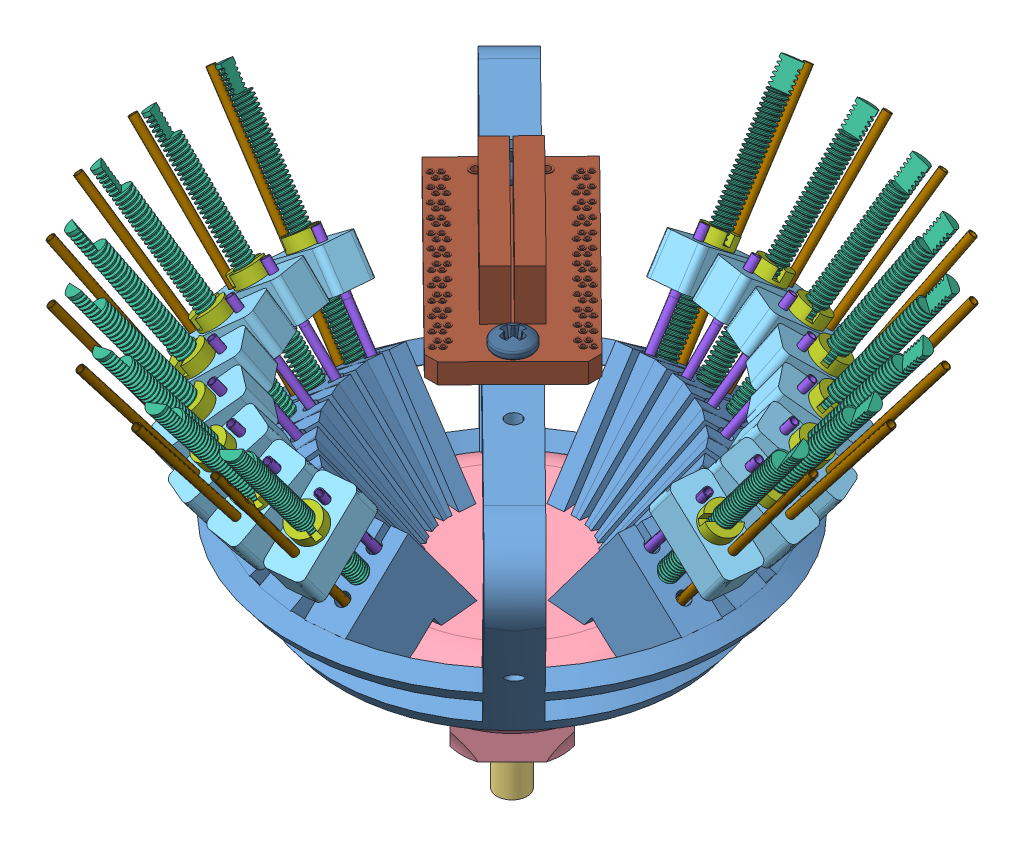
SolidWorks assembly DriveAssembly, configuration Default. Lengths in mm.
Overall size (54.83 40.66 54.81).
118 component instances, 11 part files, 91 mates.
Components (placement in the parent):
- drive_circle_16-1: drive_circle_16 [Default] at (0.3829 7.146 2.514) x (0.996757 0 0.080473) z (-0.080473 0 0.996757) size (45.82 35.06 38.44)
- 30g Tubing Curved-1: 30g Tubing Curved [Default] at (-0.6864 5.748 2.4277) x (0.996757 0 0.080473) z (-0.080473 0 0.996757) size (12.56 22.36 0.32)
- 30g Tubing Curved-5: 30g Tubing Curved [Default] at (-0.484 6 2.6618) x (0.985792 0 -0.167972) z (0.167972 0 0.985792) size (12.56 22.36 0.32)
- 30g Tubing Curved-13: 30g Tubing Curved [Default] at (-0.4207 6 2.8711) x (0.91386 0 -0.406029) z (0.406029 0 0.91386) size (12.56 22.36 0.32)
- 30g Tubing Curved-14: 30g Tubing Curved [Default] at (-0.3078 6 3.0583) x (0.78541 0 -0.618976) z (0.618976 0 0.78541) size (12.56 22.36 0.32)
- 30g Tubing Curved-15: 30g Tubing Curved [Default] at (-0.1521 6 3.2119) x (0.608386 0 -0.793641) z (0.793641 0 0.608386) size (12.56 22.36 0.32)
- 30g Tubing Curved-16: 30g Tubing Curved [Default] at (0.0366 6 3.3224) x (0.393737 0 -0.919223) z (0.919223 0 0.393737) size (12.56 22.36 0.32)
- 30g Tubing Curved-17: 30g Tubing Curved [Default] at (0.2468 6 3.3828) x (0.154736 0 -0.987956) z (0.987956 0 0.154736) size (12.56 22.36 0.32)
- 30g Tubing Curved-18: 30g Tubing Curved [Default] at (0.4654 6 3.3895) x (-0.093834 0 -0.995588) z (0.995588 0 -0.093834) size (12.56 22.36 0.32)
- 30g Tubing Curved-27: 30g Tubing Curved [Default] at (1.2594 6 2.5848) x (-0.996757 0 -0.080473) z (0.080473 0 -0.996757) size (12.56 22.36 0.32)
- 30g Tubing Curved-28: 30g Tubing Curved [Default] at (1.2497 6 2.3663) x (-0.985792 0 0.167972) z (-0.167972 0 -0.985792) size (12.56 22.36 0.32)
- 30g Tubing Curved-29: 30g Tubing Curved [Default] at (1.1865 6 2.157) x (-0.91386 0 0.406029) z (-0.406029 0 -0.91386) size (12.56 22.36 0.32)
- 30g Tubing Curved-30: 30g Tubing Curved [Default] at (1.0735 6 1.9697) x (-0.78541 0 0.618976) z (-0.618976 0 -0.78541) size (12.56 22.36 0.32)
- 30g Tubing Curved-31: 30g Tubing Curved [Default] at (0.9179 6 1.8161) x (-0.608386 0 0.793641) z (-0.793641 0 -0.608386) size (12.56 22.36 0.32)
- 30g Tubing Curved-34: 30g Tubing Curved [Default] at (0.7291 6 1.7057) x (-0.393737 0 0.919223) z (-0.919223 0 -0.393737) size (12.56 22.36 0.32)
- 30g Tubing Curved-35: 30g Tubing Curved [Default] at (0.5189 6 1.6453) x (-0.154736 0 0.987956) z (-0.987956 0 -0.154736) size (12.56 22.36 0.32)
- 30g Tubing Curved-36: 30g Tubing Curved [Default] at (0.3004 6 1.6386) x (0.093834 0 0.995588) z (-0.995588 0 0.093834) size (12.56 22.36 0.32)
- MainCanula-1: MainCanula [Default] at (0.3829 1.748 2.514) x (-0.437751 0 0.899096) z (-0.899096 0 -0.437751) size (2.41 8 2.41)
- AcrylicFill-1: AcrylicFill [Default] at (0.3829 3.9937 2.514) x (0.711094 0 0.703097) z (-0.703097 0 0.711094) size (25 12 25)
- Shuttle Assembly-18: Shuttle Assembly [Default] at (16.7091 21.9961 9.3723) x (-0.79078 0.608761 -0.063844) z (0.080473 0 -0.996757) size (6.5 25.22 3.31)
  - Shuttle-1: Shuttle [Default] at (2.5582 1.9761 5.5221) size (6.5 3 3)
  - Threaded Rod 25mm-1: Threaded Rod 25mm [Default] at (2.5582 -8.5786 5.5221) x (0.813094 0 0.582132) z (-0.582132 0 0.813094) size (1.64 25.22 1.64)
  - Grooved Nut-1: Grooved Nut [Default] at (2.5582 1.9761 5.5221) x (0.414361 0 -0.910113) z (0.910113 0 0.414361) size (2.5 4 2.5)
  - 23g Tubing 13mm-1: 23g Tubing 13mm [Default] at (4.3082 -7.0239 5.5221) size (0.64 13 0.64)
  - 23g Tubing 25mm-1: 23g Tubing 25mm [Default] at (0.8082 -8.5786 5.5221) size (0.62 25 0.62)
- Shuttle Assembly-19: Shuttle Assembly [Default] at (17.8965 21.9961 5.1316) x (-0.782081 0.608761 0.133261) z (-0.167972 0 -0.985792) size (6.5 25.22 3.31)
  - Shuttle-1: Shuttle [Default] at (2.5582 1.9761 5.5221) size (6.5 3 3)
  - Threaded Rod 25mm-1: Threaded Rod 25mm [Default] at (2.5582 -8.5786 5.5221) x (0.813094 0 0.582132) z (-0.582132 0 0.813094) size (1.64 25.22 1.64)
  - Grooved Nut-1: Grooved Nut [Default] at (2.5582 1.9761 5.5221) x (0.414361 0 -0.910113) z (0.910113 0 0.414361) size (2.5 4 2.5)
  - 23g Tubing 13mm-1: 23g Tubing 13mm [Default] at (4.3082 -7.0239 5.5221) size (0.64 13 0.64)
  - 23g Tubing 25mm-1: 23g Tubing 25mm [Default] at (0.8082 -8.5786 5.5221) size (0.62 25 0.62)
- Shuttle Assembly-20: Shuttle Assembly [Default] at (18.0009 21.9961 0.729) x (-0.725014 0.608761 0.322125) z (-0.406029 0 -0.91386) size (6.5 25.22 3.31)
  - Shuttle-1: Shuttle [Default] at (2.5582 1.9761 5.5221) size (6.5 3 3)
  - Threaded Rod 25mm-1: Threaded Rod 25mm [Default] at (2.5582 -8.5786 5.5221) x (0.813094 0 0.582132) z (-0.582132 0 0.813094) size (1.64 25.22 1.64)
  - Grooved Nut-1: Grooved Nut [Default] at (2.5582 1.9761 5.5221) x (0.414361 0 -0.910113) z (0.910113 0 0.414361) size (2.5 4 2.5)
  - 23g Tubing 13mm-1: 23g Tubing 13mm [Default] at (4.3082 -7.0239 5.5221) size (0.64 13 0.64)
  - 23g Tubing 25mm-1: 23g Tubing 25mm [Default] at (0.8082 -8.5786 5.5221) size (0.62 25 0.62)
- Shuttle Assembly-21: Shuttle Assembly [Default] at (17.0156 21.9961 -3.5632) x (-0.623108 0.608761 0.491066) z (-0.618976 0 -0.78541) size (6.5 25.22 3.31)
  - Shuttle-1: Shuttle [Default] at (2.5582 1.9761 5.5221) size (6.5 3 3)
  - Threaded Rod 25mm-1: Threaded Rod 25mm [Default] at (2.5582 -8.5786 5.5221) x (0.813094 0 0.582132) z (-0.582132 0 0.813094) size (1.64 25.22 1.64)
  - Grooved Nut-1: Grooved Nut [Default] at (2.5582 1.9761 5.5221) x (0.414361 0 -0.910113) z (0.910113 0 0.414361) size (2.5 4 2.5)
  - 23g Tubing 13mm-1: 23g Tubing 13mm [Default] at (4.3082 -7.0239 5.5221) size (0.64 13 0.64)
  - 23g Tubing 25mm-1: 23g Tubing 25mm [Default] at (0.8082 -8.5786 5.5221) size (0.62 25 0.62)
- Shuttle Assembly-22: Shuttle Assembly [Default] at (15.0017 21.9961 -7.4795) x (-0.482665 0.608761 0.629638) z (-0.793641 0 -0.608386) size (6.5 25.22 3.31)
  - Shuttle-1: Shuttle [Default] at (2.5582 1.9761 5.5221) size (6.5 3 3)
  - Threaded Rod 25mm-1: Threaded Rod 25mm [Default] at (2.5582 -8.5786 5.5221) x (0.813094 0 0.582132) z (-0.582132 0 0.813094) size (1.64 25.22 1.64)
  - Grooved Nut-1: Grooved Nut [Default] at (2.5582 1.9761 5.5221) x (0.414361 0 -0.910113) z (0.910113 0 0.414361) size (2.5 4 2.5)
  - 23g Tubing 13mm-1: 23g Tubing 13mm [Default] at (4.3082 -7.0239 5.5221) size (0.64 13 0.64)
  - 23g Tubing 25mm-1: 23g Tubing 25mm [Default] at (0.8082 -8.5786 5.5221) size (0.62 25 0.62)
- Shuttle Assembly-23: Shuttle Assembly [Default] at (12.0836 21.9961 -10.7778) x (-0.312372 0.608761 0.729269) z (-0.919223 0 -0.393737) size (6.5 25.22 3.31)
  - Shuttle-1: Shuttle [Default] at (2.5582 1.9761 5.5221) size (6.5 3 3)
  - Threaded Rod 25mm-1: Threaded Rod 25mm [Default] at (2.5582 -8.5786 5.5221) x (0.813094 0 0.582132) z (-0.582132 0 0.813094) size (1.64 25.22 1.64)
  - Grooved Nut-1: Grooved Nut [Default] at (2.5582 1.9761 5.5221) x (0.414361 0 -0.910113) z (0.910113 0 0.414361) size (2.5 4 2.5)
  - 23g Tubing 13mm-1: 23g Tubing 13mm [Default] at (4.3082 -7.0239 5.5221) size (0.64 13 0.64)
  - 23g Tubing 25mm-1: 23g Tubing 25mm [Default] at (0.8082 -8.5786 5.5221) size (0.62 25 0.62)
- Shuttle Assembly-24: Shuttle Assembly [Default] at (8.442 21.9961 -13.254) x (-0.12276 0.608761 0.783798) z (-0.987956 0 -0.154736) size (6.5 25.22 3.31)
  - Shuttle-1: Shuttle [Default] at (2.5582 1.9761 5.5221) size (6.5 3 3)
  - Threaded Rod 25mm-1: Threaded Rod 25mm [Default] at (2.5582 -8.5786 5.5221) x (0.813094 0 0.582132) z (-0.582132 0 0.813094) size (1.64 25.22 1.64)
  - Grooved Nut-1: Grooved Nut [Default] at (2.5582 1.9761 5.5221) x (0.414361 0 -0.910113) z (0.910113 0 0.414361) size (2.5 4 2.5)
  - 23g Tubing 13mm-1: 23g Tubing 13mm [Default] at (4.3082 -7.0239 5.5221) size (0.64 13 0.64)
  - 23g Tubing 25mm-1: 23g Tubing 25mm [Default] at (0.8082 -8.5786 5.5221) size (0.62 25 0.62)
- Shuttle Assembly-25: Shuttle Assembly [Default] at (4.3019 21.9961 -14.755) x (0.074444 0.608761 0.789853) z (-0.995588 0 0.093834) size (6.5 25.22 3.31)
  - Shuttle-1: Shuttle [Default] at (2.5582 1.9761 5.5221) size (6.5 3 3)
  - Threaded Rod 25mm-1: Threaded Rod 25mm [Default] at (2.5582 -8.5786 5.5221) x (0.813094 0 0.582132) z (-0.582132 0 0.813094) size (1.64 25.22 1.64)
  - Grooved Nut-1: Grooved Nut [Default] at (2.5582 1.9761 5.5221) x (0.414361 0 -0.910113) z (0.910113 0 0.414361) size (2.5 4 2.5)
  - 23g Tubing 13mm-1: 23g Tubing 13mm [Default] at (4.3082 -7.0239 5.5221) size (0.64 13 0.64)
  - 23g Tubing 25mm-1: 23g Tubing 25mm [Default] at (0.8082 -8.5786 5.5221) size (0.62 25 0.62)
- Shuttle Assembly-26: Shuttle Assembly [Default] at (-15.9433 21.9961 -4.3442) x (0.79078 0.608761 0.063844) z (-0.080473 0 0.996757) size (6.5 25.22 3.31)
  - Shuttle-1: Shuttle [Default] at (2.5582 1.9761 5.5221) size (6.5 3 3)
  - Threaded Rod 25mm-1: Threaded Rod 25mm [Default] at (2.5582 -8.5786 5.5221) x (0.813094 0 0.582132) z (-0.582132 0 0.813094) size (1.64 25.22 1.64)
  - Grooved Nut-1: Grooved Nut [Default] at (2.5582 1.9761 5.5221) x (0.414361 0 -0.910113) z (0.910113 0 0.414361) size (2.5 4 2.5)
  - 23g Tubing 13mm-1: 23g Tubing 13mm [Default] at (4.3082 -7.0239 5.5221) size (0.64 13 0.64)
  - 23g Tubing 25mm-1: 23g Tubing 25mm [Default] at (0.8082 -8.5786 5.5221) size (0.62 25 0.62)
- Shuttle Assembly-27: Shuttle Assembly [Default] at (-17.1308 21.9961 -0.1035) x (0.782081 0.608761 -0.133261) z (0.167972 0 0.985792) size (6.5 25.22 3.31)
  - Shuttle-1: Shuttle [Default] at (2.5582 1.9761 5.5221) size (6.5 3 3)
  - Threaded Rod 25mm-1: Threaded Rod 25mm [Default] at (2.5582 -8.5786 5.5221) x (0.813094 0 0.582132) z (-0.582132 0 0.813094) size (1.64 25.22 1.64)
  - Grooved Nut-1: Grooved Nut [Default] at (2.5582 1.9761 5.5221) x (0.414361 0 -0.910113) z (0.910113 0 0.414361) size (2.5 4 2.5)
  - 23g Tubing 13mm-1: 23g Tubing 13mm [Default] at (4.3082 -7.0239 5.5221) size (0.64 13 0.64)
  - 23g Tubing 25mm-1: 23g Tubing 25mm [Default] at (0.8082 -8.5786 5.5221) size (0.62 25 0.62)
- Shuttle Assembly-28: Shuttle Assembly [Default] at (-17.2351 21.9961 4.2991) x (0.725014 0.608761 -0.322125) z (0.406029 0 0.91386) size (6.5 25.22 3.31)
  - Shuttle-1: Shuttle [Default] at (2.5582 1.9761 5.5221) size (6.5 3 3)
  - Threaded Rod 25mm-1: Threaded Rod 25mm [Default] at (2.5582 -8.5786 5.5221) x (0.813094 0 0.582132) z (-0.582132 0 0.813094) size (1.64 25.22 1.64)
  - Grooved Nut-1: Grooved Nut [Default] at (2.5582 1.9761 5.5221) x (0.414361 0 -0.910113) z (0.910113 0 0.414361) size (2.5 4 2.5)
  - 23g Tubing 13mm-1: 23g Tubing 13mm [Default] at (4.3082 -7.0239 5.5221) size (0.64 13 0.64)
  - 23g Tubing 25mm-1: 23g Tubing 25mm [Default] at (0.8082 -8.5786 5.5221) size (0.62 25 0.62)
- Shuttle Assembly-29: Shuttle Assembly [Default] at (-16.2499 21.9961 8.5913) x (0.623108 0.608761 -0.491066) z (0.618976 0 0.78541) size (6.5 25.22 3.31)
  - Shuttle-1: Shuttle [Default] at (2.5582 1.9761 5.5221) size (6.5 3 3)
  - Threaded Rod 25mm-1: Threaded Rod 25mm [Default] at (2.5582 -8.5786 5.5221) x (0.813094 0 0.582132) z (-0.582132 0 0.813094) size (1.64 25.22 1.64)
  - Grooved Nut-1: Grooved Nut [Default] at (2.5582 1.9761 5.5221) x (0.414361 0 -0.910113) z (0.910113 0 0.414361) size (2.5 4 2.5)
  - 23g Tubing 13mm-1: 23g Tubing 13mm [Default] at (4.3082 -7.0239 5.5221) size (0.64 13 0.64)
  - 23g Tubing 25mm-1: 23g Tubing 25mm [Default] at (0.8082 -8.5786 5.5221) size (0.62 25 0.62)
- Shuttle Assembly-30: Shuttle Assembly [Default] at (-14.2359 21.9961 12.5076) x (0.482665 0.608761 -0.629638) z (0.793641 0 0.608386) size (6.5 25.22 3.31)
  - Shuttle-1: Shuttle [Default] at (2.5582 1.9761 5.5221) size (6.5 3 3)
  - Threaded Rod 25mm-1: Threaded Rod 25mm [Default] at (2.5582 -8.5786 5.5221) x (0.813094 0 0.582132) z (-0.582132 0 0.813094) size (1.64 25.22 1.64)
  - Grooved Nut-1: Grooved Nut [Default] at (2.5582 1.9761 5.5221) x (0.414361 0 -0.910113) z (0.910113 0 0.414361) size (2.5 4 2.5)
  - 23g Tubing 13mm-1: 23g Tubing 13mm [Default] at (4.3082 -7.0239 5.5221) size (0.64 13 0.64)
  - 23g Tubing 25mm-1: 23g Tubing 25mm [Default] at (0.8082 -8.5786 5.5221) size (0.62 25 0.62)
- Shuttle Assembly-32: Shuttle Assembly [Default] at (-11.3179 21.9961 15.8059) x (0.312372 0.608761 -0.729269) z (0.919223 0 0.393737) size (6.5 25.22 3.31)
  - Shuttle-1: Shuttle [Default] at (2.5582 1.9761 5.5221) size (6.5 3 3)
  - Threaded Rod 25mm-1: Threaded Rod 25mm [Default] at (2.5582 -8.5786 5.5221) x (0.813094 0 0.582132) z (-0.582132 0 0.813094) size (1.64 25.22 1.64)
  - Grooved Nut-1: Grooved Nut [Default] at (2.5582 1.9761 5.5221) x (0.414361 0 -0.910113) z (0.910113 0 0.414361) size (2.5 4 2.5)
  - 23g Tubing 13mm-1: 23g Tubing 13mm [Default] at (4.3082 -7.0239 5.5221) size (0.64 13 0.64)
  - 23g Tubing 25mm-1: 23g Tubing 25mm [Default] at (0.8082 -8.5786 5.5221) size (0.62 25 0.62)
- Shuttle Assembly-33: Shuttle Assembly [Default] at (-7.6762 21.9961 18.2821) x (0.12276 0.608761 -0.783798) z (0.987956 0 0.154736) size (6.5 25.22 3.31)
  - Shuttle-1: Shuttle [Default] at (2.5582 1.9761 5.5221) size (6.5 3 3)
  - Threaded Rod 25mm-1: Threaded Rod 25mm [Default] at (2.5582 -8.5786 5.5221) x (0.813094 0 0.582132) z (-0.582132 0 0.813094) size (1.64 25.22 1.64)
  - Grooved Nut-1: Grooved Nut [Default] at (2.5582 1.9761 5.5221) x (0.414361 0 -0.910113) z (0.910113 0 0.414361) size (2.5 4 2.5)
  - 23g Tubing 13mm-1: 23g Tubing 13mm [Default] at (4.3082 -7.0239 5.5221) size (0.64 13 0.64)
  - 23g Tubing 25mm-1: 23g Tubing 25mm [Default] at (0.8082 -8.5786 5.5221) size (0.62 25 0.62)
- Shuttle Assembly-34: Shuttle Assembly [Default] at (-3.5361 21.9961 19.7831) x (-0.074444 0.608761 -0.789853) z (0.995588 0 -0.093834) size (6.5 25.22 3.31)
  - Shuttle-1: Shuttle [Default] at (2.5582 1.9761 5.5221) size (6.5 3 3)
  - Threaded Rod 25mm-1: Threaded Rod 25mm [Default] at (2.5582 -8.5786 5.5221) x (0.813094 0 0.582132) z (-0.582132 0 0.813094) size (1.64 25.22 1.64)
  - Grooved Nut-1: Grooved Nut [Default] at (2.5582 1.9761 5.5221) x (0.414361 0 -0.910113) z (0.910113 0 0.414361) size (2.5 4 2.5)
  - 23g Tubing 13mm-1: 23g Tubing 13mm [Default] at (4.3082 -7.0239 5.5221) size (0.64 13 0.64)
  - 23g Tubing 25mm-1: 23g Tubing 25mm [Default] at (0.8082 -8.5786 5.5221) size (0.62 25 0.62)
- McMasterCarr_0-80_91772A052-1: McMasterCarr_0-80_91772A052 [91772A052] at (-5.6677 33.0313 -3.4559) x (1 0 0) z (0 1 0) size (2.95 2.95 6.38)
- McMasterCarr_0-80_91772A052-2: McMasterCarr_0-80_91772A052 [91772A052] at (6.4334 33.0313 8.484) x (1 0 0) z (0 1 0) size (2.95 2.95 6.38)
- EIB_64_Omnetics-1: EIB_64_Omnetics [Default] at (0.3829 34.6188 2.514) x (0.711833 0 0.702349) z (-0.702349 0 0.711833) size (20 5.6 10)
Mates (geometry in assembly coordinates):
- Concentric1: concentric aligned: circle of drive_circle_16-1; circle of 30g Tubing Curved-1
- Concentric5: concentric aligned: circle of 30g Tubing Curved-5; circle of drive_circle_16-1
- Concentric6: concentric aligned: circle of 30g Tubing Curved-13; circle of drive_circle_16-1
- Concentric7: concentric aligned: circle of 30g Tubing Curved-14; circle of drive_circle_16-1
- Concentric8: concentric aligned: circle of 30g Tubing Curved-15; circle of drive_circle_16-1
- Concentric9: concentric aligned: circle of 30g Tubing Curved-16; circle of drive_circle_16-1
- Concentric10: concentric aligned: circle of 30g Tubing Curved-17; circle of drive_circle_16-1
- Concentric11: concentric aligned: circle of 30g Tubing Curved-18; circle of drive_circle_16-1
- Parallel1: parallel anti-aligned: plane of 30g Tubing Curved-5 through (-0.2868 0 2.6282) normal (0 -1 0); plane of assembly through (0 0 0) normal (0 1 0)
- Parallel2: parallel anti-aligned: plane of 30g Tubing Curved-1 through (-0.4871 -0.252 2.4438) normal (0 -1 0); plane of assembly through (0 0 0) normal (0 1 0)
- Parallel3: parallel anti-aligned: plane of 30g Tubing Curved-18 through (0.4466 0 3.1904) normal (0 -1 0); plane of assembly through (0 0 0) normal (0 1 0)
- Parallel4: parallel anti-aligned: plane of 30g Tubing Curved-17 through (0.2777 0 3.1852) normal (0 -1 0); plane of assembly through (0 0 0) normal (0 1 0)
- Parallel5: parallel anti-aligned: plane of 30g Tubing Curved-16 through (0.1154 0 3.1385) normal (0 -1 0); plane of assembly through (0 0 0) normal (0 1 0)
- Parallel6: parallel anti-aligned: plane of 30g Tubing Curved-15 through (-0.0304 0 3.0532) normal (0 -1 0); plane of assembly through (0 0 0) normal (0 1 0)
- Parallel7: parallel anti-aligned: plane of 30g Tubing Curved-14 through (-0.1507 0 2.9346) normal (0 -1 0); plane of assembly through (0 0 0) normal (0 1 0)
- Parallel8: parallel anti-aligned: plane of 30g Tubing Curved-13 through (-0.238 0 2.7899) normal (0 -1 0); plane of assembly through (0 0 0) normal (0 1 0)
- Distance9: distance = 0 mm aligned: plane of 30g Tubing Curved-1 through (-0.4871 -0.252 2.4438) normal (0 -1 0); plane of MainCanula-1 through (0.3829 -0.252 2.514) normal (0 -1 0)
- Concentric12: concentric aligned: line of drive_circle_16-1 through (0.3829 7.146 2.514) axis (0 1 0); circle of MainCanula-1
- Parallel11: parallel anti-aligned: plane of MainCanula-1 through (0.3829 7.748 2.514) normal (0 1 0); plane of AcrylicFill-1 through (0.3829 3.9937 2.514) normal (0 -1 0)
- Concentric13: concentric aligned: circle of AcrylicFill-1; circle of MainCanula-1
- StabilizerAndDriveConcentric: concentric aligned: circle of drive_circle_16-1; circle of Shuttle Assembly-18/23g Tubing 25mm-1
- BrassNutAndDriveConcentric: concentric anti-aligned: circle of drive_circle_16-1; circle of Shuttle Assembly-18/Grooved Nut-1
- ShuttleHeight: distance = 7 mm aligned: plane of Shuttle Assembly-18/Shuttle-1 through (18.15 27.5012 3.9485) normal (0.606787 0.793353 0.048989); plane of drive_circle_16-1 through (11.4531 23.9262 1.9029) normal (0.606787 0.793353 0.048989)
- Concentric36: concentric aligned: circle of Shuttle Assembly-19/23g Tubing 25mm-1; circle of drive_circle_16-1
- Concentric37: concentric anti-aligned: unknown of Shuttle Assembly-19/Grooved Nut-1; unknown of drive_circle_16-1
- Distance11: distance = 7 mm aligned: plane of Shuttle Assembly-19/Shuttle-1 through (17.9545 27.5012 -0.48) normal (0.600112 0.793353 -0.102255); plane of drive_circle_16-1 through (10.96 23.9262 -0.8098) normal (0.600112 0.793353 -0.102255)
- Concentric38: concentric aligned: circle of Shuttle Assembly-20/23g Tubing 25mm-1; circle of drive_circle_16-1
- Concentric39: concentric anti-aligned: unknown of Shuttle Assembly-20/Grooved Nut-1; unknown of drive_circle_16-1
- Distance12: distance = 7 mm aligned: plane of Shuttle Assembly-20/Shuttle-1 through (16.6724 27.5012 -4.7234) normal (0.556323 0.793353 -0.247175); plane of drive_circle_16-1 through (9.8128 23.9262 -3.3171) normal (0.556323 0.793353 -0.247175)
- Concentric40: concentric aligned: circle of drive_circle_16-1; circle of Shuttle Assembly-21/23g Tubing 25mm-1
- Concentric41: concentric anti-aligned: unknown of drive_circle_16-1; unknown of Shuttle Assembly-21/Grooved Nut-1
- Distance13: distance = 7 mm aligned: plane of Shuttle Assembly-21/Shuttle-1 through (14.3827 27.5012 -8.5191) normal (0.478127 0.793353 -0.376808); plane of drive_circle_16-1 through (8.0823 23.9262 -5.4636) normal (0.478127 0.793353 -0.376808)
- Concentric42: concentric aligned: circle of drive_circle_16-1; circle of Shuttle Assembly-22/23g Tubing 25mm-1
- Concentric43: concentric anti-aligned: unknown of drive_circle_16-1; unknown of Shuttle Assembly-22/Grooved Nut-1
- Distance14: distance = 7 mm aligned: plane of Shuttle Assembly-22/Shuttle-1 through (11.2273 27.5012 -11.6325) normal (0.370362 0.793353 -0.483138); plane of drive_circle_16-1 through (5.8757 23.9262 -7.1168) normal (0.370362 0.793353 -0.483138)
- Concentric44: concentric aligned: circle of drive_circle_16-1; circle of Shuttle Assembly-23/23g Tubing 25mm-1
- Concentric45: concentric anti-aligned: unknown of drive_circle_16-1; unknown of Shuttle Assembly-23/Grooved Nut-1
- Distance15: distance = 7 mm aligned: plane of Shuttle Assembly-23/Shuttle-1 through (7.4012 27.5012 -13.871) normal (0.239692 0.793353 -0.559588); plane of drive_circle_16-1 through (3.3293 23.9262 -8.1744) normal (0.239692 0.793353 -0.559588)
- Concentric46: concentric aligned: circle of drive_circle_16-1; circle of Shuttle Assembly-24/23g Tubing 25mm-1
- Concentric47: concentric anti-aligned: unknown of drive_circle_16-1; unknown of Shuttle Assembly-24/Grooved Nut-1
- Distance16: distance = 7 mm aligned: plane of Shuttle Assembly-24/Shuttle-1 through (3.141 27.5012 -15.0962) normal (0.094197 0.793353 -0.601429); plane of drive_circle_16-1 through (0.6007 23.9262 -8.571) normal (0.094197 0.793353 -0.601429)
- Concentric48: concentric aligned: circle of drive_circle_16-1; circle of Shuttle Assembly-25/23g Tubing 25mm-1
- Concentric49: concentric anti-aligned: unknown of drive_circle_16-1; unknown of Shuttle Assembly-25/Grooved Nut-1
- Distance17: distance = 7 mm aligned: plane of Shuttle Assembly-25/Shuttle-1 through (-1.2897 27.5012 -15.2322) normal (-0.057123 0.793353 -0.606075); plane of drive_circle_16-1 through (-2.1413 23.9262 -8.2819) normal (-0.057123 0.793353 -0.606075)
- Concentric50: concentric anti-aligned: circle of drive_circle_16-1; circle of Shuttle Assembly-26/23g Tubing 25mm-1
- Concentric51: concentric aligned: unknown of drive_circle_16-1; unknown of Shuttle Assembly-26/Grooved Nut-1
- Distance18: distance = 7 mm aligned: plane of Shuttle Assembly-26/Shuttle-1 through (-17.3842 27.5012 1.0796) normal (-0.606787 0.793353 -0.048989); plane of drive_circle_16-1 through (-10.446 23.9262 0.1349) normal (-0.606787 0.793353 -0.048989)
- Concentric52: concentric anti-aligned: circle of drive_circle_16-1; circle of Shuttle Assembly-27/23g Tubing 25mm-1
- Concentric53: concentric aligned: unknown of drive_circle_16-1; unknown of Shuttle Assembly-27/Grooved Nut-1
- Distance19: distance = 7 mm aligned: plane of Shuttle Assembly-27/Shuttle-1 through (-17.1888 27.5012 5.5081) normal (-0.600112 0.793353 0.102255); plane of drive_circle_16-1 through (-10.6982 23.9262 2.8806) normal (-0.600112 0.793353 0.102255)
- Concentric54: concentric anti-aligned: circle of drive_circle_16-1; circle of Shuttle Assembly-28/23g Tubing 25mm-1
- Concentric55: concentric aligned: unknown of drive_circle_16-1; unknown of Shuttle Assembly-28/Grooved Nut-1
- Distance20: distance = 7 mm aligned: plane of Shuttle Assembly-28/Shuttle-1 through (-15.9066 27.5012 9.7515) normal (-0.556323 0.793353 0.247175); plane of drive_circle_16-1 through (-10.2651 23.9262 5.6036) normal (-0.556323 0.793353 0.247175)
- Concentric56: concentric anti-aligned: circle of drive_circle_16-1; circle of Shuttle Assembly-29/23g Tubing 25mm-1
- Concentric57: concentric aligned: unknown of drive_circle_16-1; unknown of Shuttle Assembly-29/Grooved Nut-1
- Distance21: distance = 7 mm aligned: plane of Shuttle Assembly-29/Shuttle-1 through (-13.617 27.5012 13.5472) normal (-0.478127 0.793353 0.376808); plane of drive_circle_16-1 through (-9.1735 23.9262 8.1355) normal (-0.478127 0.793353 0.376808)
- Concentric58: concentric anti-aligned: circle of drive_circle_16-1; circle of Shuttle Assembly-30/23g Tubing 25mm-1
- Concentric59: concentric aligned: unknown of drive_circle_16-1; unknown of Shuttle Assembly-30/Grooved Nut-1
- Distance22: distance = 7 mm aligned: plane of Shuttle Assembly-30/Shuttle-1 through (-10.4616 27.5012 16.6606) normal (-0.370362 0.793353 0.483138); plane of drive_circle_16-1 through (-7.4908 23.9262 10.3198) normal (-0.370362 0.793353 0.483138)
- Concentric61: concentric anti-aligned: circle of Shuttle Assembly-32/23g Tubing 25mm-1; circle of drive_circle_16-1
- Concentric62: concentric aligned: unknown of Shuttle Assembly-32/Grooved Nut-1; unknown of drive_circle_16-1
- Distance23: distance = 7 mm aligned: plane of Shuttle Assembly-32/Shuttle-1 through (-6.6355 27.5012 18.8991) normal (-0.239692 0.793353 0.559588); plane of drive_circle_16-1 through (-5.3212 23.9262 12.0213) normal (-0.239692 0.793353 0.559588)
- Concentric63: concentric anti-aligned: circle of drive_circle_16-1; circle of Shuttle Assembly-33/23g Tubing 25mm-1
- Concentric64: concentric aligned: unknown of Shuttle Assembly-33/Grooved Nut-1; unknown of drive_circle_16-1
- Distance24: distance = 7 mm aligned: plane of Shuttle Assembly-33/Shuttle-1 through (-2.3753 27.5012 20.1243) normal (-0.094197 0.793353 0.601429); plane of drive_circle_16-1 through (-2.7989 23.9262 13.1348) normal (-0.094197 0.793353 0.601429)
- Concentric65: concentric anti-aligned: circle of drive_circle_16-1; circle of Shuttle Assembly-34/23g Tubing 25mm-1
- Concentric66: concentric aligned: unknown of drive_circle_16-1; unknown of Shuttle Assembly-34/Grooved Nut-1
- Distance25: distance = 7 mm aligned: plane of Shuttle Assembly-34/Shuttle-1 through (2.0555 27.5012 20.2603) normal (0.057123 0.793353 0.606075); plane of drive_circle_16-1 through (-0.0797 23.9262 13.5915) normal (0.057123 0.793353 0.606075)
- Concentric67: concentric anti-aligned: unknown of drive_circle_16-1; unknown of 30g Tubing Curved-27
- Parallel12: parallel anti-aligned: plane of 30g Tubing Curved-27 through (1.06 0 2.5687) normal (0 -1 0); plane of assembly through (0 0 0) normal (0 1 0)
- Concentric68: concentric anti-aligned: unknown of drive_circle_16-1; unknown of 30g Tubing Curved-28
- Parallel13: parallel anti-aligned: plane of 30g Tubing Curved-28 through (1.0526 0 2.3999) normal (0 -1 0); plane of assembly through (0 0 0) normal (0 1 0)
- Concentric69: concentric anti-aligned: unknown of drive_circle_16-1; unknown of 30g Tubing Curved-29
- Parallel14: parallel anti-aligned: plane of 30g Tubing Curved-29 through (1.0037 0 2.2382) normal (0 -1 0); plane of assembly through (0 0 0) normal (0 1 0)
- Concentric70: concentric anti-aligned: unknown of drive_circle_16-1; unknown of 30g Tubing Curved-30
- Parallel15: parallel anti-aligned: plane of 30g Tubing Curved-30 through (0.9164 0 2.0935) normal (0 -1 0); plane of assembly through (0 0 0) normal (0 1 0)
- Concentric71: concentric anti-aligned: unknown of drive_circle_16-1; unknown of 30g Tubing Curved-31
- Parallel16: parallel anti-aligned: plane of 30g Tubing Curved-31 through (0.7962 0 1.9749) normal (0 -1 0); plane of assembly through (0 0 0) normal (0 1 0)
- Parallel19: parallel anti-aligned: plane of 30g Tubing Curved-34 through (0.6504 0 1.8896) normal (0 -1 0); plane of assembly through (0 0 0) normal (0 1 0)
- Concentric73: concentric anti-aligned: circle of drive_circle_16-1; circle of 30g Tubing Curved-34
- Concentric74: concentric anti-aligned: unknown of drive_circle_16-1; unknown of 30g Tubing Curved-35
- Parallel20: parallel anti-aligned: plane of 30g Tubing Curved-35 through (0.488 0 1.8429) normal (0 -1 0); plane of assembly through (0 0 0) normal (0 1 0)
- Concentric75: concentric anti-aligned: unknown of drive_circle_16-1; unknown of 30g Tubing Curved-36
- Parallel21: parallel anti-aligned: plane of 30g Tubing Curved-36 through (0.3191 0 1.8377) normal (0 -1 0); plane of assembly through (0 0 0) normal (0 1 0)
- Concentric76: concentric anti-aligned: circle of drive_circle_16-1; circle of EIB_64_Omnetics-1
- Concentric77: concentric anti-aligned: circle of drive_circle_16-1; circle of EIB_64_Omnetics-1
- Concentric78: concentric aligned: circle of McMasterCarr_0-80_91772A052-2; circle of EIB_64_Omnetics-1
- Concentric79: concentric aligned: circle of McMasterCarr_0-80_91772A052-1; circle of EIB_64_Omnetics-1
- Coincident1: coincident aligned: plane of McMasterCarr_0-80_91772A052-1 through (-5.6677 36.2063 -3.4559) normal (0 -1 0); plane of McMasterCarr_0-80_91772A052-2 through (6.4334 36.2063 8.484) normal (0 -1 0)
- Coincident2: coincident anti-aligned: plane of McMasterCarr_0-80_91772A052-2 through (6.4334 36.2063 8.484) normal (0 -1 0); plane of EIB_64_Omnetics-1 through (0.3829 36.2063 2.514) normal (0 1 0)
- Coincident3: coincident anti-aligned: plane of drive_circle_16-1 through (20.4403 34.6188 24.7628) normal (0 1 0); plane of EIB_64_Omnetics-1 through (0.3829 34.6188 2.514) normal (0 -1 0)
